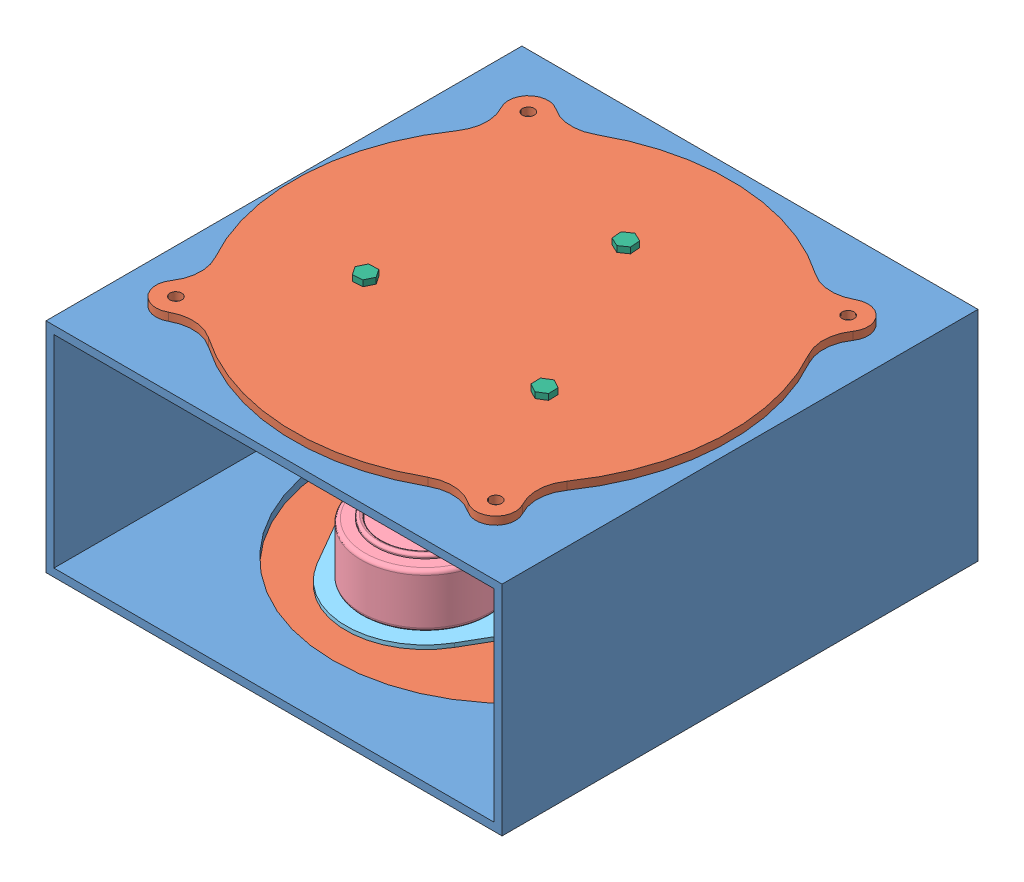
SolidWorks assembly BasicAlphaSenseBlock, configuration Default. Lengths in mm.
Overall size (150.28 62 280).
35 component instances, 8 part files, 4 mates.
Components (placement in the parent):
- Pipe-1: Pipe [Default] at (-129.2419 -18.1482 220.5288) size (115 55 280)
- ClipAssembly-1: ClipAssembly [Default] at (-129.2419 -47.6482 80.5288) size (143.51 26 143.51)
  - Clip-1: Clip [Default] at origin size (110 2 110)
  - Gasket-1: Gasket [Default] at (0 3 0) x (0.631829 0 0.775108) z (0.775108 0 -0.631829) size (102 2 102)
  - Alphasense-1: Alphasense [Default] at (18.9035 10 -10.9139) x (-0.5 0 0.866025) z (-0.866025 0 -0.5) size (77.81 19.5 72.74)
    - Alphasense-1: Alphasense [Default] at origin size (32.33 14.5 32.33)
    - Alphasense-2: Alphasense [Default] at (37.807 0 0) size (32.33 14.5 32.33)
    - Alphasense-3: Alphasense [Default] at (18.9035 0 32.7418) size (32.33 14.5 32.33)
    - AlphasenseBoard-1: AlphasenseBoard [Default] at (18.9035 -1 10.9139) size (77.81 5 72.74)
  - Thread-1: Thread [Default] at (-23.7412 0 13.707) x (-0.8278 0 -0.561024) z (0.561024 0 -0.8278) size (5 13.5 4.35)
  - Thread-2: Thread [Default] at (0 0 -27.4139) x (-0.125019 0 0.992154) z (-0.992154 0 -0.125019) size (5 13.5 4.35)
  - Thread-3: Thread [Default] at (23.7412 0 13.707) x (0.402458 0 0.915438) z (-0.915438 0 0.402458) size (5 13.5 4.35)
  - ClipSeparator-1: ClipSeparator [Default] at (-23.7412 2 13.707) x (0.880706 0 0.473664) z (-0.473664 0 0.880706) size (5.29 7 6)
  - ClipSeparator-2: ClipSeparator [Default] at (23.7412 2 13.707) size (5.29 7 6)
  - ClipSeparator-3: ClipSeparator [Default] at (0 2 -27.4139) x (0.093101 0 0.995657) z (-0.995657 0 0.093101) size (5.29 7 6)
  - ClipBolt-1: ClipBolt [Default] at (23.7412 12 13.707) x (-0.837169 0 -0.546944) z (-0.546944 0 0.837169) size (5.92 2 5.62)
  - ClipBolt-2: ClipBolt [Default] at (-23.7412 10 13.707) size (5.92 2 5.62)
  - ClipBolt-3: ClipBolt [Default] at (0 10 -27.4139) size (5.92 2 5.62)
- ClipAssembly-2: ClipAssembly [Default] at (-129.2419 11.3518 80.5288) x (-0.998828 0 -0.048392) z (-0.048392 0 0.998828) size (143.51 26 143.51)
  - Clip-1: Clip [Default] at origin size (110 2 110)
  - Gasket-1: Gasket [Default] at (0 3 0) x (0.631829 0 0.775108) z (0.775108 0 -0.631829) size (102 2 102)
  - Alphasense-1: Alphasense [Default] at (18.9035 10 -10.9139) x (-0.5 0 0.866025) z (-0.866025 0 -0.5) size (77.81 19.5 72.74)
    - Alphasense-1: Alphasense [Default] at origin size (32.33 14.5 32.33)
    - Alphasense-2: Alphasense [Default] at (37.807 0 0) size (32.33 14.5 32.33)
    - Alphasense-3: Alphasense [Default] at (18.9035 0 32.7418) size (32.33 14.5 32.33)
    - AlphasenseBoard-1: AlphasenseBoard [Default] at (18.9035 -1 10.9139) size (77.81 5 72.74)
  - Thread-1: Thread [Default] at (-23.7412 0 13.707) x (-0.8278 0 -0.561024) z (0.561024 0 -0.8278) size (5 13.5 4.35)
  - Thread-2: Thread [Default] at (0 0 -27.4139) x (-0.125019 0 0.992154) z (-0.992154 0 -0.125019) size (5 13.5 4.35)
  - Thread-3: Thread [Default] at (23.7412 0 13.707) x (0.402458 0 0.915438) z (-0.915438 0 0.402458) size (5 13.5 4.35)
  - ClipSeparator-1: ClipSeparator [Default] at (-23.7412 2 13.707) x (0.880706 0 0.473664) z (-0.473664 0 0.880706) size (5.29 7 6)
  - ClipSeparator-2: ClipSeparator [Default] at (23.7412 2 13.707) size (5.29 7 6)
  - ClipSeparator-3: ClipSeparator [Default] at (0 2 -27.4139) x (0.093101 0 0.995657) z (-0.995657 0 0.093101) size (5.29 7 6)
  - ClipBolt-1: ClipBolt [Default] at (23.7412 12 13.707) x (-0.837169 0 -0.546944) z (-0.546944 0 0.837169) size (5.92 2 5.62)
  - ClipBolt-2: ClipBolt [Default] at (-23.7412 10 13.707) size (5.92 2 5.62)
  - ClipBolt-3: ClipBolt [Default] at (0 10 -27.4139) size (5.92 2 5.62)
Mates (geometry in assembly coordinates):
- Coincident1: coincident anti-aligned: plane of Pipe-1 through (-71.7419 -45.6482 -106.9467) normal (0 -1 0); plane of ClipAssembly-1/Clip-1 through (-178.0175 -45.6482 42.0946) normal (0 1 0)
- Concentric1: concentric anti-aligned: circle of Pipe-1; circle of ClipAssembly-1/Gasket-1
- Coincident2: coincident anti-aligned: plane of Pipe-1 through (-71.7419 9.3518 -106.9467) normal (0 1 0); plane of ClipAssembly-2/Clip-1 through (-78.6635 9.3518 44.5) normal (0 -1 0)
- Concentric2: concentric anti-aligned: circle of Pipe-1; circle of ClipAssembly-2/Gasket-1
